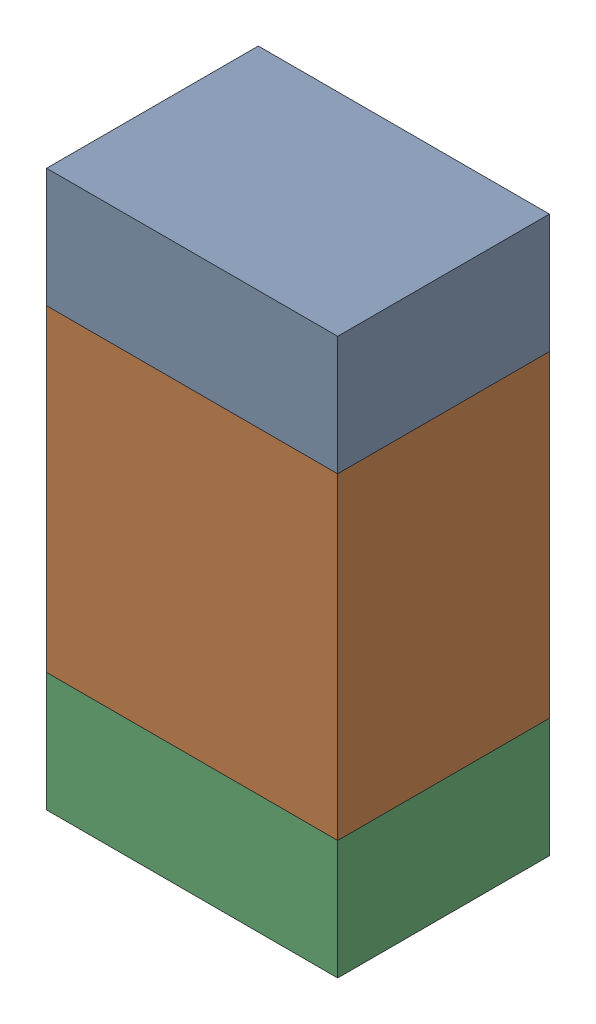
SolidWorks assembly R311_2PCB, configuration Default. Lengths in mm.
Overall size (0.55 1.05 0.4).
6 component instances, 2 part files, 0 mates.
Components (placement in the parent):
- 846483288-1: 846483288 [Default] at (126.2001 96.7126 -2.0638) size (0.55 0.22 0.4)
  - Extruded_12-1: Extruded_12 [Default] at origin size (0.55 0.22 0.4)
- 846483424-1: 846483424 [Default] at (126.2001 96.3001 -2.0638) size (0.55 0.6 0.4)
  - Extruded_13-1: Extruded_13 [Default] at origin size (0.55 0.6 0.4)
- 846483288-2: 846483288 [Default] at (126.2001 95.8876 -2.0638) size (0.55 0.22 0.4)
  - Extruded_12-1: Extruded_12 [Default] at origin size (0.55 0.22 0.4)
